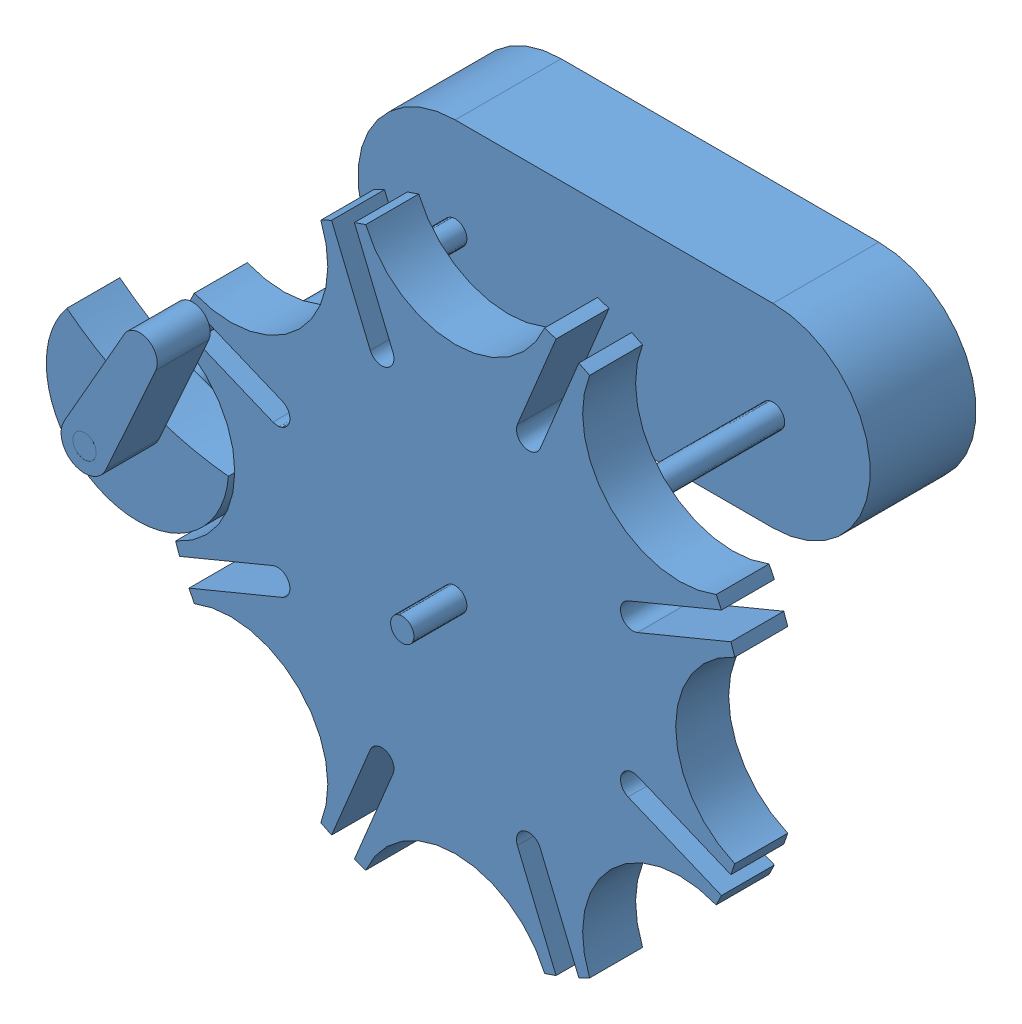
SolidWorks assembly Animacion_Ginebra_2, configuration Default. Lengths in mm.
Overall size (39.39 31.68 27).
3 component instances, 1 part files, 3 mates.
Components (placement in the parent):
- Rueda_Ginebra_7-1: Rueda_Ginebra_7 [Soporte] at (11.6462 31.5759 55.7866) size (29.02 11.02 27)
- Rueda_Ginebra_7-2: Rueda_Ginebra_7 [Disco_bloqueador] at (11.5913 30.1709 55.7866) x (0.996949 -0.078053 0) z (0 0 1) size (10.33 12.53 6)
- Rueda_Ginebra_7-3: Rueda_Ginebra_7 [Default] at (11.6462 31.5759 55.7866) size (31.68 31.68 3)
Mates (geometry in assembly coordinates):
- Coincidente1: coincident: circle of Rueda_Ginebra_7-1; circle of Rueda_Ginebra_7-2
- Concéntrica1: concentric: circle of Rueda_Ginebra_7-1; circle of Rueda_Ginebra_7-3
- Coincidente3: coincident: plane of Rueda_Ginebra_7-2 through (-2.9187 40.1509 55.7866) normal (0 0 1); plane of Rueda_Ginebra_7-3 through (11.6462 31.5759 55.7866) normal (0 0 1)
